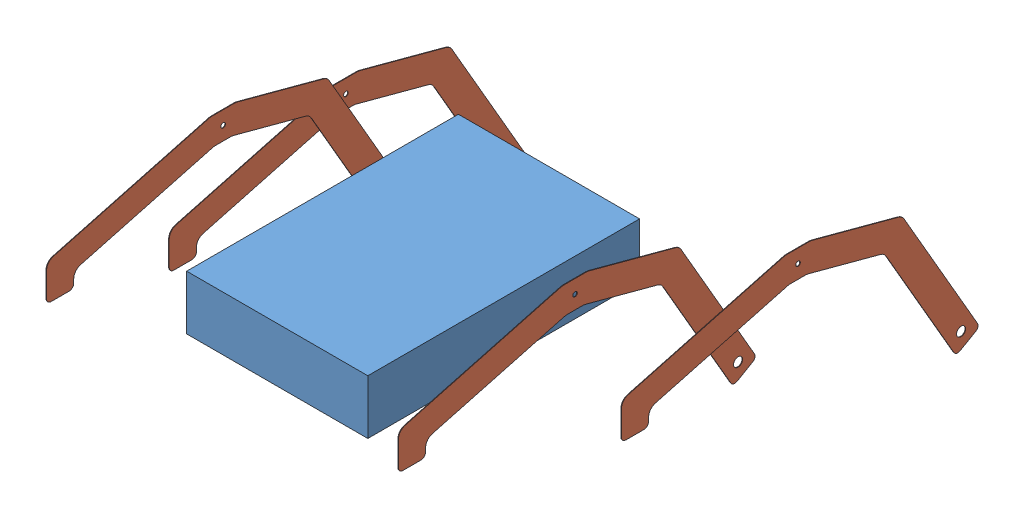
SolidWorks assembly Apoapsis Mk II, configuration Default. Lengths in mm.
Overall size (788.86 845.97 1837.32).
5 component instances, 2 part files, 0 mates.
Components (placement in the parent):
- Temporary Chassis Box-1: Temporary Chassis Box [Default] at (366.6665 188.5151 638.4268) size (508 152.4 762)
- Rocker-2: Rocker [Default] at (683.2045 312.4362 502.4608) size (1.59 478.59 999.9)
- Rocker-3: Rocker [Default] at (822.4776 213.2178 16.3945) size (1.59 478.59 999.9)
- Rocker-4: Rocker [Default] at (47.9415 580.5945 853.822) size (1.59 478.59 999.9)
- Rocker-5: Rocker [Default] at (35.2016 472.1314 497.1488) size (1.59 478.59 999.9)
